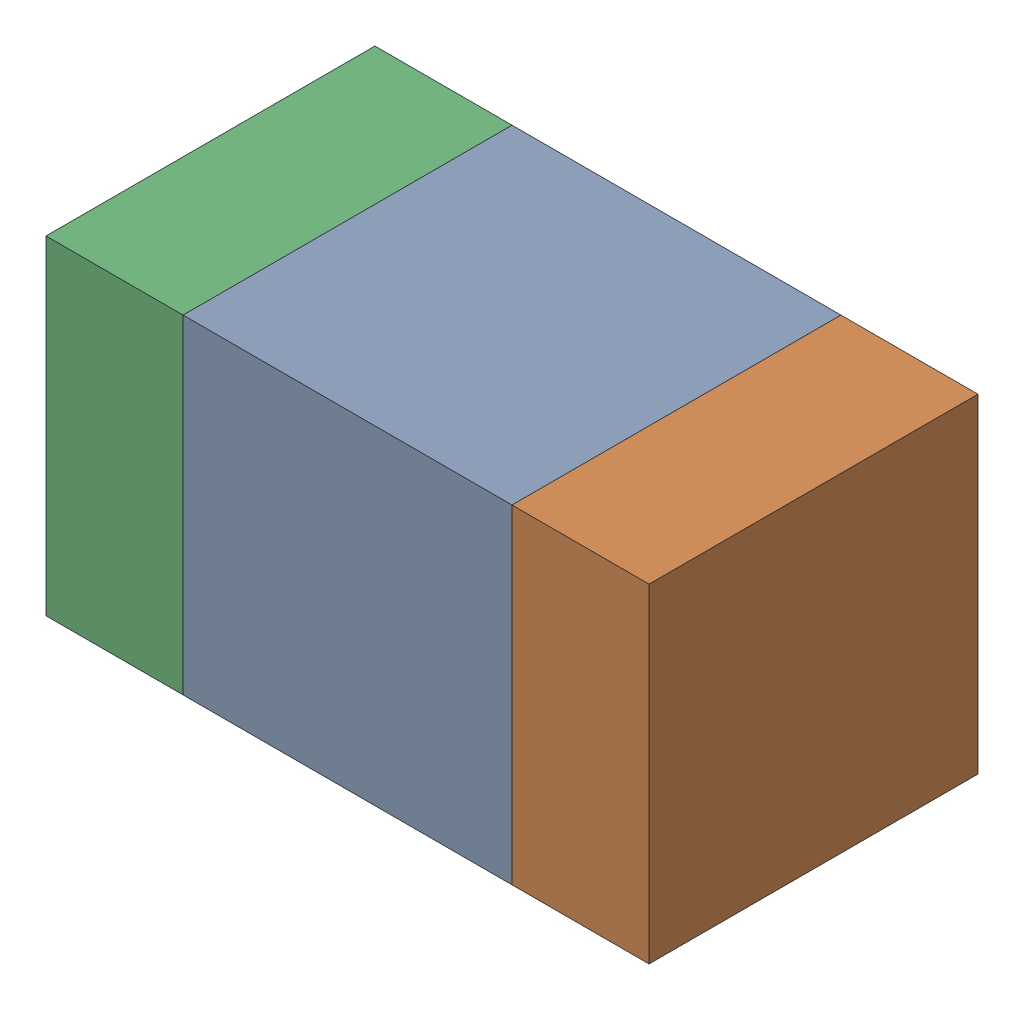
SolidWorks assembly C325_2PCB, configuration Default. Lengths in mm.
Overall size (1.1 0.6 0.6).
6 component instances, 2 part files, 0 mates.
Components (placement in the parent):
- 761606048-1: 761606048 [Default] at (135.4 90.3 -2.2638) size (0.6 0.6 0.6)
  - Extruded_9-1: Extruded_9 [Default] at origin size (0.6 0.6 0.6)
- 854785160-1: 854785160 [Default] at (135.825 90.3 -2.2638) size (0.25 0.6 0.6)
  - Extruded_19-1: Extruded_19 [Default] at origin size (0.25 0.6 0.6)
- 854785160-2: 854785160 [Default] at (134.975 90.3 -2.2638) size (0.25 0.6 0.6)
  - Extruded_19-1: Extruded_19 [Default] at origin size (0.25 0.6 0.6)
